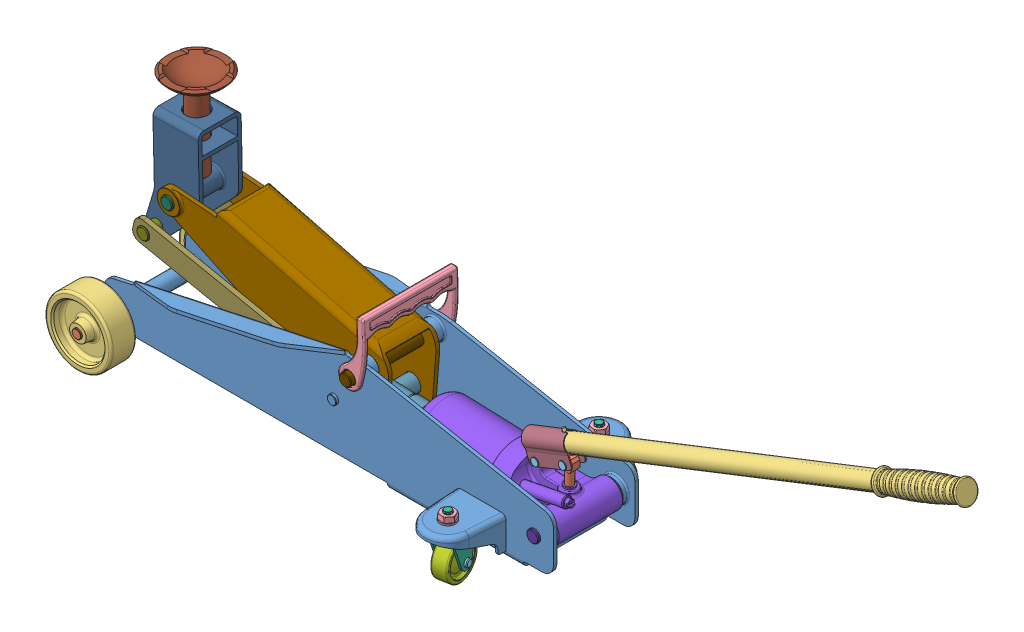
SolidWorks assembly Dizalica 2, configuration Default. Lengths in mm.
Overall size (1123.55 373.4 278.26).
33 component instances, 23 part files, 53 mates.
Components (placement in the parent):
- frame-1: frame [Default] at (-68.2964 302.8792 437.3817) size (596 130.51 260.5)
- pin front wheels-1: pin front wheels [Default] at (-67.4908 303.3553 437.3817) size (12 12 215)
- front wheel-1: front wheel [Default] at (-67.4908 303.3553 525.8817) size (88 88 34)
- tocak-1: tocak [Default] at (465.2386 301.9932 508.0241) x (0.984561 0 -0.175042) z (0.175042 0 0.984561) size (36 96.08 70.3) (flexible)
  - nut1 7-1: nut1 7 [Default] at (-51.6884 27.4861 20.8824) x (-0.230089 0 -0.97317) z (0 1 0) size (20 20 9.74)
  - pin wheel (1) 6-1: pin wheel (1) 6 [Default] at (-69.6884 -21.1139 10.8824) x (0 0 -1) z (1 0 0) size (10 10 36)
  - support 5-1: support 5 [Default] at (-51.6884 -30.1139 10.8824) size (30 69.93 30)
  - wheel 4-1: wheel 4 [Default] at (-51.6884 -21.1139 10.8824) x (0 -0.779257 0.626704) z (-1 0 0) size (50 50 20)
- front wheel-2: front wheel [Default] at (-67.4908 303.3553 348.8817) x (0.999809 0.019567 0) z (0 0 1) size (88 88 34)
- tocak-2: tocak [Default] at (472.8338 301.9932 347.2019) x (0.844272 0 0.535915) z (-0.535915 0 0.844272) size (36 96.08 70.3) (flexible)
  - nut1 7-1: nut1 7 [Default] at (-51.6884 27.4861 20.8824) x (-0.826977 0 -0.562235) z (0 1 0) size (20 20 9.74)
  - pin wheel (1) 6-1: pin wheel (1) 6 [Default] at (-69.6884 -21.1139 10.8824) x (0 0 -1) z (1 0 0) size (10 10 36)
  - support 5-1: support 5 [Default] at (-51.6884 -30.1139 10.8824) size (30 69.93 30)
  - wheel 4-1: wheel 4 [Default] at (-51.6884 -21.1139 10.8824) x (0 -0.779257 0.626704) z (-1 0 0) size (50 50 20)
- cylinder-1: cylinder [Default] at (292.1323 331.9999 437.3817) x (0 0 -1) z (0.999347 -0.036146 0) size (88 82 215.5)
- lifting arm 1-1: lifting arm 1 [Default] at (-15.0462 446.3141 437.3817) x (0.967687 -0.252153 0) z (0 0 1) size (319.02 106.7 76)
- saddle support 2-1: saddle support 2 [Default] at (-45.0939 533.6261 437.3817) x (0.999727 0.023359 0) z (0 0 1) size (72.5 146 57)
- saddle-1: saddle [Default] at (-13.3969 461.3468 437.3817) x (0.999727 0.023359 0) z (0 0 1) size (76.57 119.3 76.57)
- leveling arm-1: leveling arm [Default] at (91.7356 375.7997 477.0067) x (0.979612 -0.200899 0) z (0 0 1) size (296 28 6.5)
- socket 3-1: socket 3 [Default] at (455.8608 389.9203 437.3817) x (0 0 -1) z (-0.9312 -0.364508 0) size (24 37 60)
- rod-1: rod [Default] at (399.5641 328.1142 437.3817) x (0 0 1) z (-0.999347 0.036146 0) size (70 30 172.3)
- leveling arm-2: leveling arm [Default] at (91.7356 375.7997 391.2567) x (0.979612 -0.200899 0) z (0 0 1) size (296 28 6.5)
- pin 11-1: pin 11 [Default] at (-15.0462 446.3141 437.3817) size (16 16 82)
- pin 22-1: pin 22 [Default] at (-39.5324 402.7203 437.3817) size (16 16 96)
- pin 33-1: pin 33 [Default] at (489.0036 324.8792 437.3817) size (16 16 119)
- pin 44-1: pin 44 [Default] at (249.0036 388.8792 437.3817) size (16 16 136)
- pin 55-1: pin 55 [Default] at (223.0036 348.8792 497.0067) x (-0.923728 -0.383049 0) z (0 0 -1) size (20 20 22)
- pin cylindar-1: pin cylindar [Default] at (478.5029 338.8829 437.3817) x (0.999347 -0.036146 0) z (0 0 1) size (14 44 12)
- handle-1: handle [Default] at (661.1904 470.2943 437.3817) x (-0.364508 0.9312 0) z (-0.9312 -0.364508 0) size (30 30 620)
- carry handle 8-1: carry handle 8 [Default] at (263.9895 451.8925 437.3817) x (0 0 1) z (-0.999485 -0.032085 0) size (126 89.25 36.25)
- pin 55-2: pin 55 [Default] at (223.0036 348.8792 377.7567) size (20 20 22)
- pin pin cilindar-1: pin pin cilindar [Default] at (443.3717 363.5539 422.3817) x (0.998522 -0.054349 0) z (0 0 1) size (10 10 26)
- pin pin cilindar-2: pin pin cilindar [Default] at (479.9126 377.8574 422.3817) x (0.994947 -0.100399 0) z (0 0 1) size (10 10 26)
Mates (geometry in assembly coordinates):
- Concentric1: concentric: cylinder of assembly; cylinder of assembly; cylinder of frame-1 through (-67.4908 303.3553 307.1317) axis (0 0 1) radius 6; cylinder of pin front wheels-1 through (-67.4908 303.3553 544.8817) axis (0 0 -1) radius 6
- Concentric2: concentric: cylinder of assembly; cylinder of assembly; cylinder of pin front wheels-1 through (-67.4908 303.3553 544.8817) axis (0 0 -1) radius 6; cylinder of front wheel-1 through (-67.4908 303.3553 542.8817) axis (0 0 -1) radius 6
- Coincident1: coincident: circle of assembly; plane of assembly; circle of frame-1; plane of front wheel-1 through (-67.4908 303.3553 508.8817) normal (0 0 -1)
- Width1: width: plane of assembly; plane of assembly; plane of assembly; plane of assembly; plane of pin front wheels-1 through (-67.4908 303.3553 544.8817) normal (0 0 1); plane of pin front wheels-1 through (-67.4908 303.3553 329.8817) normal (0 0 -1); plane of frame-1 through (-68.2964 302.8792 381.1317) normal (0 0 -1); plane of frame-1 through (-68.2964 302.8792 493.6317) normal (0 0 1)
- Concentric5: concentric: cylinder of assembly; cylinder of assembly; cylinder of pin front wheels-1 through (-67.4908 303.3553 544.8817) axis (0 0 -1) radius 6; cylinder of front wheel-2 through (-67.4908 303.3553 365.8817) axis (0 0 -1) radius 6
- Coincident3: coincident: plane of assembly; plane of assembly; plane of frame-1 through (-67.4908 303.3553 365.8817) normal (0 0 -1); plane of front wheel-2 through (-67.4908 303.3553 365.8817) normal (0 0 1)
- Concentric6: concentric: circle of assembly; cylinder of assembly; circle of frame-1; cylinder of tocak-1/support 5-1 through (418.0036 341.4792 537.6317) axis (0 1 0) radius 10
- Coincident4: coincident: plane of assembly; plane of assembly; plane of frame-1 through (418.0036 326.4792 537.6317) normal (0 -1 0); plane of tocak-1/support 5-1 through (419.754 326.4792 547.4773) normal (0 1 0)
- Concentric7: concentric: circle of frame-1; cylinder of tocak-2/support 5-1 through (418.0036 341.4792 337.1317) axis (0 1 0) radius 10
- Coincident5: coincident: plane of frame-1 through (418.0036 326.4792 537.6317) normal (0 -1 0); plane of tocak-2/support 5-1 through (412.6444 326.4792 345.5744) normal (0 1 0)
- Concentric8: concentric: cylinder of assembly; cylinder of assembly; cylinder of frame-1 through (249.0036 388.8792 493.6317) axis (0 0 -1) radius 8; cylinder of lifting arm 1-1 through (249.0036 388.8792 471.3817) axis (0 0 -1) radius 8
- Width2: width: plane of assembly; plane of assembly; plane of assembly; plane of assembly; plane of lifting arm 1-1 through (-15.0462 446.3141 471.3817) normal (0 0 1); plane of lifting arm 1-1 through (-15.0462 446.3141 403.3817) normal (0 0 -1); plane of frame-1 through (-68.2964 302.8792 381.1317) normal (0 0 -1); plane of frame-1 through (-68.2964 302.8792 493.6317) normal (0 0 1)
- Concentric9: concentric: cylinder of assembly; cylinder of assembly; cylinder of frame-1 through (489.0036 324.8792 381.1317) axis (0 0 1) radius 8; cylinder of cylinder-1 through (489.0036 324.8792 393.3817) axis (0 0 1) radius 8
- Width3: width: plane of assembly; plane of assembly; plane of assembly; plane of assembly; plane of cylinder-1 through (489.0036 324.8792 393.3817) normal (0 0 -1); plane of cylinder-1 through (489.0036 324.8792 481.3817) normal (0 0 1); plane of frame-1 through (-68.2964 302.8792 381.1317) normal (0 0 -1); plane of frame-1 through (-68.2964 302.8792 493.6317) normal (0 0 1)
- Concentric10: concentric: cylinder of assembly; cylinder of assembly; cylinder of cylinder-1 through (422.0473 327.301 437.3817) axis (-0.999347 0.036146 0) radius 15; cylinder of rod-1 through (269.649 332.8131 437.3817) axis (0.999347 -0.036146 0) radius 15
- Concentric11: concentric: cylinder of assembly; cylinder of assembly; cylinder of lifting arm 1-1 through (241.3675 333.8361 471.3817) axis (0 0 -1) radius 11.5; cylinder of rod-1 through (241.3675 333.8361 472.3817) axis (0 0 -1) radius 11
- LimitAngle1: limit planar angle = 0.466204 rad: plane of assembly; plane of assembly; plane of lifting arm 1-1 through (47.5068 468.252 471.3817) normal (0.252153 0.967687 0); plane of frame-1 through (-77.0202 343.549 437.3817) normal (-0.209731 0.977759 0)
- Concentric12: concentric: cylinder of assembly; cylinder of assembly; cylinder of lifting arm 1-1 through (-15.0462 446.3141 471.3817) axis (0 0 -1) radius 8; cylinder of saddle support 2-1 through (-15.0462 446.3141 465.8817) axis (0 0 -1) radius 8
- Width4: width: plane of assembly; plane of assembly; plane of assembly; plane of assembly; plane of saddle support 2-1 through (-39.5324 402.7203 465.8817) normal (0 0 1); plane of saddle support 2-1 through (-39.5324 402.7203 408.8817) normal (0 0 -1); plane of lifting arm 1-1 through (-15.0462 446.3141 403.3817) normal (0 0 -1); plane of lifting arm 1-1 through (-15.0462 446.3141 471.3817) normal (0 0 1)
- Concentric13: concentric: cylinder of assembly; cylinder of assembly; cylinder of frame-1 through (223.0036 348.8792 493.6317) axis (0 0 -1) radius 6; cylinder of leveling arm-1 through (223.0036 348.8792 483.5067) axis (0 0 -1) radius 8
- Concentric14: concentric: cylinder of assembly; cylinder of assembly; cylinder of saddle support 2-1 through (-39.5324 402.7203 465.8817) axis (0 0 -1) radius 8; cylinder of leveling arm-1 through (-39.5324 402.7203 483.5067) axis (0 0 -1) radius 8
- Width5: width: plane of assembly; plane of assembly; plane of assembly; plane of assembly; plane of leveling arm-1 through (91.7356 375.7997 483.5067) normal (0 0 1); plane of leveling arm-1 through (91.7356 375.7997 477.0067) normal (0 0 -1); plane of frame-1 through (-68.2964 302.8792 489.1317) normal (0 0 -1); plane of lifting arm 1-1 through (-15.0462 446.3141 471.3817) normal (0 0 1)
- Concentric16: concentric: cylinder of assembly; cylinder of assembly; cylinder of saddle support 2-1 through (-14.8685 524.3296 437.3817) axis (-0.023359 0.999727 0) radius 12.5; cylinder of saddle-1 through (-13.3969 461.3468 437.3817) axis (0.023359 -0.999727 0) radius 12.5
- Distance2: distance = 40 mm: plane of assembly; plane of assembly; plane of saddle-1 through (-13.3969 461.3468 437.3817) normal (0.023359 -0.999727 0); plane of saddle support 2-1 through (-56.8175 500.3431 413.8817) normal (0.023359 -0.999727 0)
- Concentric17: concentric: cylinder of assembly; cylinder of assembly; cylinder of frame-1 through (223.0036 348.8792 381.1317) axis (0 0 1) radius 6; cylinder of leveling arm-2 through (223.0036 348.8792 397.7567) axis (0 0 -1) radius 8
- Concentric18: concentric: cylinder of assembly; cylinder of assembly; cylinder of saddle support 2-1 through (-39.5324 402.7203 465.8817) axis (0 0 -1) radius 8; cylinder of leveling arm-2 through (-39.5324 402.7203 397.7567) axis (0 0 -1) radius 8
- Width6: width: plane of assembly; plane of assembly; plane of assembly; plane of assembly; plane of leveling arm-2 through (91.7356 375.7997 391.2567) normal (0 0 -1); plane of leveling arm-2 through (91.7356 375.7997 397.7567) normal (0 0 1); plane of frame-1 through (-68.2964 302.8792 385.6317) normal (0 0 1); plane of lifting arm 1-1 through (-15.0462 446.3141 403.3817) normal (0 0 -1)
- Concentric19: concentric: cylinder of assembly; cylinder of assembly; cylinder of frame-1 through (249.0036 388.8792 493.6317) axis (0 0 -1) radius 8; cylinder of pin 44-1 through (249.0036 388.8792 505.3817) axis (0 0 -1) radius 8
- Width7: width: plane of assembly; plane of assembly; plane of assembly; plane of assembly; plane of pin 44-1 through (249.0036 388.8792 505.3817) normal (0 0 1); plane of pin 44-1 through (249.0036 388.8792 369.3817) normal (0 0 -1); plane of frame-1 through (-68.2964 302.8792 381.1317) normal (0 0 -1); plane of frame-1 through (-68.2964 302.8792 493.6317) normal (0 0 1)
- Concentric20: concentric: cylinder of assembly; cylinder of assembly; cylinder of pin 44-1 through (249.0036 388.8792 505.3817) axis (0 0 -1) radius 8; cylinder of carry handle 8-1 through (249.0036 388.8792 500.3817) axis (0 0 -1) radius 8.25
- Width8: width: plane of assembly; plane of assembly; plane of assembly; plane of assembly; plane of carry handle 8-1 through (90.065 433.8028 500.3817) normal (0 0 1); plane of carry handle 8-1 through (90.065 433.8028 374.3817) normal (0 0 -1); plane of frame-1 through (-68.2964 302.8792 493.6317) normal (0 0 1); plane of frame-1 through (-68.2964 302.8792 381.1317) normal (0 0 -1)
- Concentric21: concentric: cylinder of assembly; cylinder of assembly; cylinder of frame-1 through (489.0036 324.8792 493.6317) axis (0 0 -1) radius 8; cylinder of pin 33-1 through (489.0036 324.8792 496.8817) axis (0 0 -1) radius 8
- Width9: width: plane of assembly; plane of assembly; plane of assembly; plane of assembly; plane of pin 33-1 through (489.0036 324.8792 496.8817) normal (0 0 1); plane of pin 33-1 through (489.0036 324.8792 377.8817) normal (0 0 -1); plane of frame-1 through (-68.2964 302.8792 381.1317) normal (0 0 -1); plane of frame-1 through (-68.2964 302.8792 493.6317) normal (0 0 1)
- Concentric22: concentric: cylinder of assembly; cylinder of assembly; cylinder of frame-1 through (223.0036 348.8792 493.6317) axis (0 0 -1) radius 6; cylinder of pin 55-1 through (223.0036 348.8792 477.0067) axis (0 0 1) radius 6
- Coincident7: coincident: plane of assembly; plane of assembly; plane of leveling arm-1 through (91.7356 375.7997 477.0067) normal (0 0 -1); plane of pin 55-1 through (223.0036 348.8792 477.0067) normal (0 0 1)
- Concentric23: concentric: cylinder of assembly; cylinder of assembly; cylinder of frame-1 through (223.0036 348.8792 381.1317) axis (0 0 1) radius 6; cylinder of pin 55-2 through (223.0036 348.8792 397.7567) axis (0 0 -1) radius 6
- Coincident8: coincident: plane of assembly; plane of assembly; plane of leveling arm-2 through (91.7356 375.7997 397.7567) normal (0 0 1); plane of pin 55-2 through (223.0036 348.8792 397.7567) normal (0 0 -1)
- Concentric24: concentric: cylinder of assembly; cylinder of assembly; cylinder of leveling arm-1 through (-39.5324 402.7203 483.5067) axis (0 0 -1) radius 8; cylinder of pin 22-1 through (-39.5324 402.7203 485.3817) axis (0 0 -1) radius 8
- Width10: width: plane of assembly; plane of assembly; plane of assembly; plane of assembly; plane of pin 22-1 through (-39.5324 402.7203 485.3817) normal (0 0 1); plane of pin 22-1 through (-39.5324 402.7203 389.3817) normal (0 0 -1); plane of leveling arm-2 through (91.7356 375.7997 391.2567) normal (0 0 -1); plane of leveling arm-1 through (91.7356 375.7997 483.5067) normal (0 0 1)
- Concentric25: concentric: cylinder of assembly; cylinder of assembly; cylinder of lifting arm 1-1 through (-15.0462 446.3141 471.3817) axis (0 0 -1) radius 8; cylinder of pin 11-1 through (-15.0462 446.3141 478.3817) axis (0 0 -1) radius 8
- Width11: width: plane of assembly; plane of assembly; plane of assembly; plane of assembly; plane of pin 11-1 through (-15.0462 446.3141 478.3817) normal (0 0 1); plane of pin 11-1 through (-15.0462 446.3141 396.3817) normal (0 0 -1); plane of lifting arm 1-1 through (-15.0462 446.3141 399.3817) normal (0 0 -1); plane of lifting arm 1-1 through (-15.0462 446.3141 475.3817) normal (0 0 1)
- Concentric26: concentric: cylinder of assembly; cylinder of assembly; cylinder of cylinder-1 through (478.5891 341.2664 437.3817) axis (0.036146 0.999347 0) radius 5; cylinder of pin cylindar-1 through (479.5872 368.8633 437.3817) axis (-0.036146 -0.999347 0) radius 5
- Parallel1: parallel: plane of assembly; plane of assembly; plane of cylinder-1 through (399.8119 328.1052 445.3817) normal (0 0 1); plane of pin cylindar-1 through (473.0979 383.1072 443.3817) normal (0 0 1)
- Concentric27: concentric: cylinder of assembly; cylinder of assembly; cylinder of socket 3-1 through (479.9126 377.8574 459.0436) axis (0 0 -1) radius 3; cylinder of pin cylindar-1 through (479.9126 377.8574 431.3807) axis (0 0 1) radius 3
- Width12: width: plane of assembly; plane of assembly; plane of assembly; plane of assembly; plane of socket 3-1 through (503.3747 401.3958 447.3817) normal (0 0 1); plane of socket 3-1 through (503.3747 401.3958 427.3817) normal (0 0 -1); plane of pin cylindar-1 through (473.0979 383.1072 443.3817) normal (0 0 1); plane of pin cylindar-1 through (473.0979 383.1072 431.3817) normal (0 0 -1)
- Concentric28: concentric: cylinder of assembly; cylinder of assembly; cylinder of cylinder-1 through (443.3717 363.5539 393.3817) axis (0 0 1) radius 3; cylinder of pin pin cilindar-1 through (443.3717 363.5539 447.3817) axis (0 0 -1) radius 3
- Coincident9: coincident: plane of assembly; plane of assembly; plane of socket 3-1 through (503.3747 401.3958 447.3817) normal (0 0 1); plane of pin pin cilindar-1 through (443.3717 363.5539 447.3817) normal (0 0 -1)
- Slot1: slot: cylinder of pin pin cilindar-1 through (443.3717 363.5539 447.3817) axis (0 0 -1) radius 3; cylinder of socket 3-1 through (439.8709 362.1836 459.0436) axis (0 0 -1) radius 3; cylinder of socket 3-1 through (443.5957 363.6416 459.0436) axis (0 0 -1) radius 3
- Concentric29: concentric: cylinder of assembly; cylinder of assembly; cylinder of pin cylindar-1 through (479.9126 377.8574 431.3807) axis (0 0 1) radius 3; cylinder of pin pin cilindar-2 through (479.9126 377.8574 447.3817) axis (0 0 -1) radius 3
- Coincident10: coincident: plane of assembly; plane of assembly; plane of socket 3-1 through (503.3747 401.3958 447.3817) normal (0 0 1); plane of pin pin cilindar-2 through (479.9126 377.8574 447.3817) normal (0 0 -1)
- Concentric31: concentric: cylinder of assembly; cylinder of assembly; cylinder of socket 3-1 through (427.9248 378.985 437.3817) axis (0.9312 0.364508 0) radius 10.5; cylinder of handle-1 through (428.3904 379.1673 437.3817) axis (0.9312 0.364508 0) radius 10
- Tangent8: tangent: plane of assembly; cylinder of assembly; plane of socket 3-1 through (474.9504 397.3927 437.3817) normal (0.9312 0.364508 0); cylinder of handle-1 through (482.2811 384.1518 437.3817) axis (-0.364508 0.9312 0) radius 2
- Coincident13: coincident: plane of assembly; plane of assembly; plane of socket 3-1 through (455.8608 389.9203 437.3817) normal (0 0 -1); plane of handle-1 through (661.1904 470.2943 437.3817) normal (0 0 -1)
